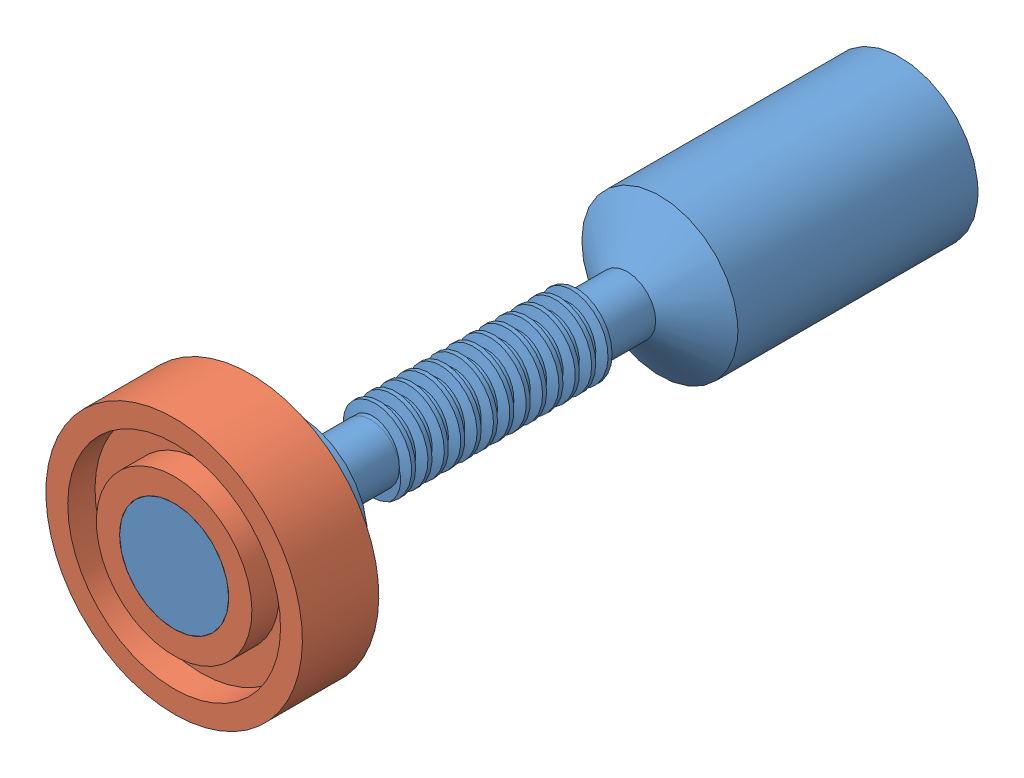
SolidWorks assembly WormShaftAssembly, configuration Default. Lengths in mm.
Overall size (61.66 61.66 133).
2 component instances, 2 part files, 2 mates.
Components (placement in the parent):
- WormShaft-1: WormShaft [Default] at (13.2502 29.7484 -27.2026) size (28.6 28.6 133)
- WormShaftBearing-1: WormShaftBearing [Default] at (13.2502 29.7484 91.7974) x (-0.392082 -0.91993 0) z (0 0 1) size (47 47 14)
Mates (geometry in assembly coordinates):
- Concentric1: concentric aligned: cylinder of WormShaft-1 through (13.2502 29.7484 105.7974) axis (0 0 -1) radius 10; cylinder of WormShaftBearing-1 through (13.2502 29.7484 105.7974) axis (0 0 -1) radius 10
- Coincident1: coincident aligned: plane of WormShaft-1 through (13.2502 29.7484 105.7974) normal (0 0 1); plane of WormShaftBearing-1 through (13.2502 29.7484 105.7974) normal (0 0 1)
